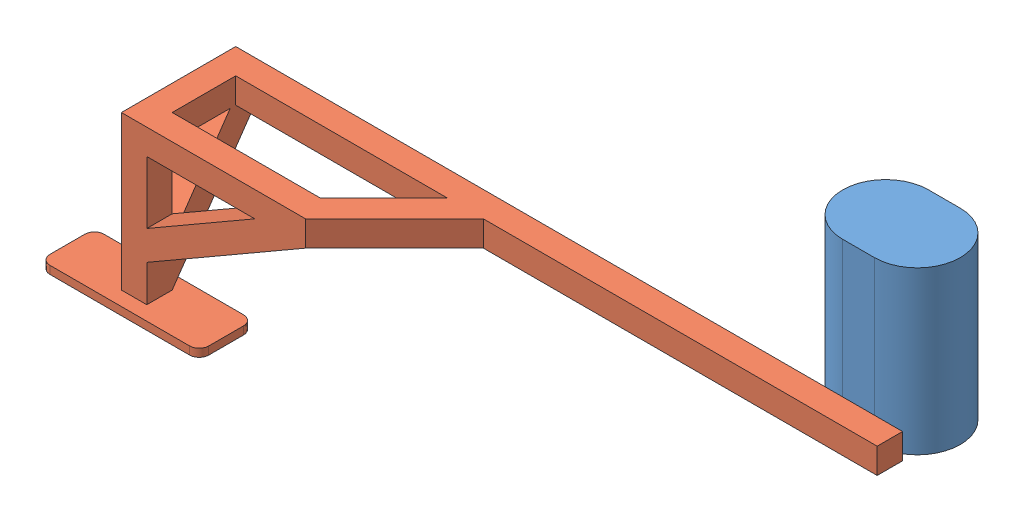
SolidWorks assembly _EJECTOR, configuration Default. Lengths in mm.
Overall size (235.66 93.92 67.5).
2 component instances, 2 part files, 6 mates.
Components (placement in the parent):
- Part2^_EJECTOR-1: Part2^_EJECTOR [Default] at (192.1636 42.9244 -45.5) x (1 0 0) z (0 1 0) size (37 27 51) (virtual)
- Part7^_EJECTOR-1: Part7^_EJECTOR [Default] x (1 0 0) z (0 1 0) size (231 40.5 50.92) (virtual)
Mates (geometry in assembly coordinates):
- InPlace2: in place: plane of Part7^_EJECTOR-1 through (0 0 0) normal (0 1 0); moOrthogonalPlaneRef_w of Part7^_EJECTOR-1 through (0 0 0) normal (0 0 -1); plane of Part7^_EJECTOR-1 through (0 0 0) normal (1 0 0); unknown of Part7^_EJECTOR-1
- Coincident1: coincident aligned: 
- Coincident2: coincident aligned: plane of Part7^_EJECTOR-1 through (0 0 0) normal (0 0 -1)
- Coincident3: coincident anti-aligned: plane of Part7^_EJECTOR-1 through (0 0 0) normal (1 0 0)
- Coincident4: coincident anti-aligned: plane of Part2^_EJECTOR-1 through (187.1636 92.9244 -32) normal (0 0 1); plane of Part7^_EJECTOR-1 through (0 0 -32) normal (0 0 -1)
- Coincident5: coincident aligned: plane of Part2^_EJECTOR-1 through (187.1636 42.9244 -45.5) normal (0 -1 0); plane of Part7^_EJECTOR-1 through (-4 42.9244 -24) normal (0 -1 0)
